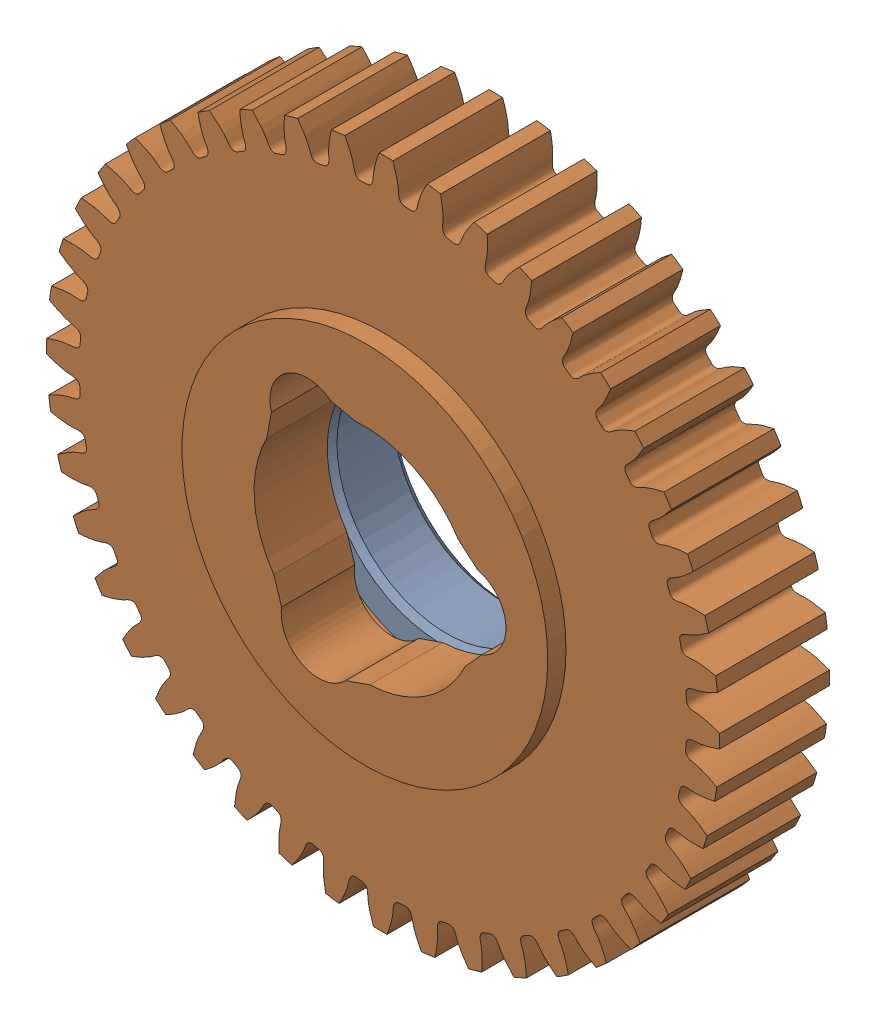
SolidWorks assembly 217-2709-101 Rev1, configuration Default. Lengths in mm.
Overall size (62.31 62.31 12.7).
2 component instances, 2 part files, 0 mates.
Components (placement in the parent):
- 217-2428-022 Rev1-1: 217-2428-022 Rev1 [Default] at origin size (28.57 28.57 6.1)
- 217-2709-001_44t Steel-1: 217-2709-001_44t Steel [Default] at (0 0 3.302) x (0.062728 -0.998031 0) z (0 0 1) size (58.74 58.74 11.11)
